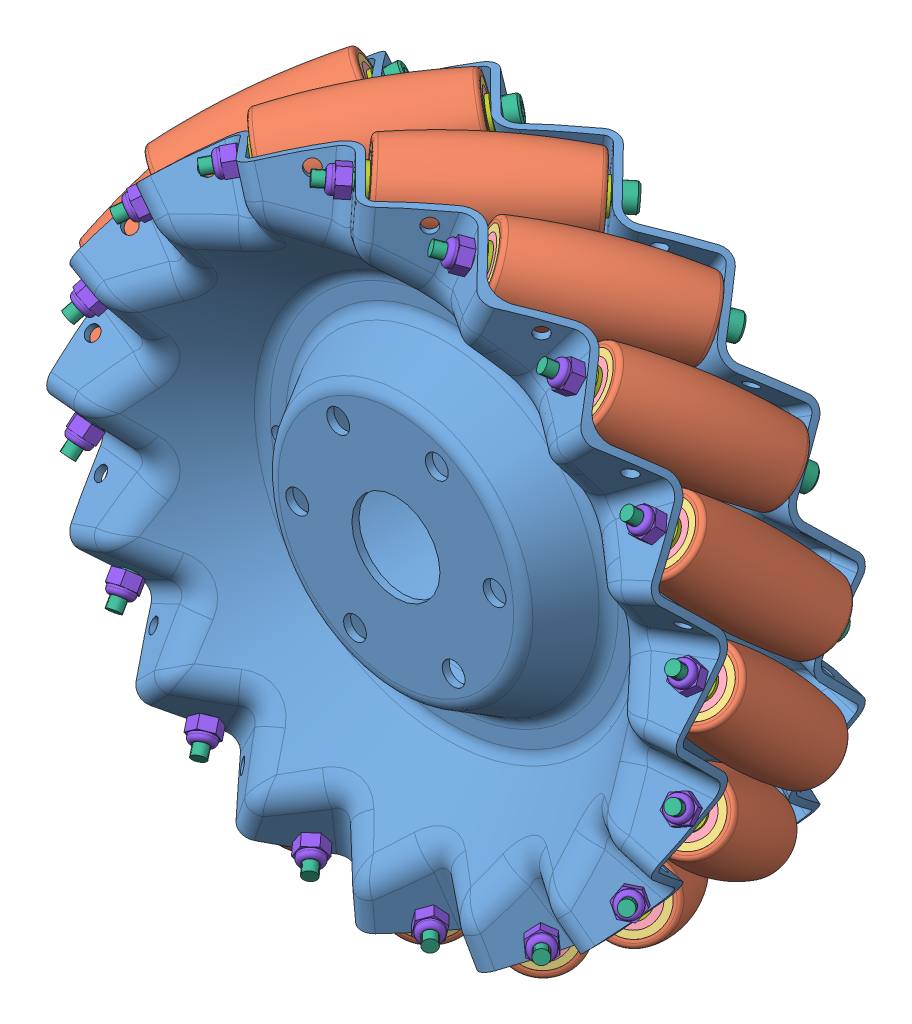
SolidWorks assembly 麦轮组装左, configuration 默认. Lengths in mm.
Overall size (168 168 53.18).
162 component instances, 8 part files, 5 mates.
Components (placement in the parent):
- 麦轮钣金-1: 麦轮钣金 [默认] at (-20.9276 7.6858 132.4522) size (142.88 142.88 24.05)
- 麦轮钣金-2: 麦轮钣金 [默认] at (-20.9276 7.6858 129.2518) x (-0.980785 -0.19509 0) z (0 0 -1) size (142.88 142.88 24.05)
- 滚花橡胶轮组装-1: 滚花橡胶轮组装 [默认] at (60.4121 -1.9858 154.8754) x (0.932849 -0.320965 -0.163627) z (-0.338043 -0.622763 -0.705615) size (18.5 18.5 53)
  - 滚花橡胶轮外-1: 滚花橡胶轮外 [默认] at (-9.896 1.7835 38.5971) size (18.5 18.5 38)
  - 滚花铝柱-1: 滚花铝柱 [默认] at (-9.896 1.7835 38) x (0.787441 0.61639 0) z (-0.61639 0.787441 0) size (13 38 13)
  - 轴承5X10X4-1: 轴承5X10X4 [默认] at (-9.896 1.7835 55) x (0.442498 0.896769 0) z (-0.896769 0.442498 0) size (10 4 10)
  - 轴承5X10X4-2: 轴承5X10X4 [默认] at (-9.896 1.7835 21) x (0.442498 0.896769 0) z (-0.896769 0.442498 0) size (10 4 10)
  - 铜管3X5-1: 铜管3X5 [默认] at (-9.896 1.7835 38) x (0.823254 0.567673 0) z (-0.567673 0.823254 0) size (5 38 5)
  - 螺丝-1: 螺丝 [默认] at (-9.896 1.7835 59.6) x (-0.462621 0.886556 0) z (0 0 1) size (5.5 5.5 53)
  - 垫片-1: 垫片 [默认] at (-9.896 1.7835 57) x (1 0 0) z (0 -1 0) size (7 0.8 7)
  - 垫片-2: 垫片 [默认] at (-9.896 1.7835 19) x (0.746862 -0.664979 0) z (0.664979 0.746862 0) size (7 0.8 7)
  - 螺母-1: 螺母 [默认] at (-9.896 1.7835 16.2) x (-0.766894 0.641774 0) z (0 0 -1) size (6.35 5.5 4.25)
- 滚花橡胶轮组装-2: 滚花橡胶轮组装 [默认] at (57.9216 29.8777 154.8754) x (0.984668 0.060453 -0.163627) z (-0.073989 -0.704722 -0.705615) size (18.5 18.5 53)
  - 滚花橡胶轮外-1: 滚花橡胶轮外 [默认] at (-9.896 1.7835 38.5971) size (18.5 18.5 38)
  - 滚花铝柱-1: 滚花铝柱 [默认] at (-9.896 1.7835 38) x (0.787441 0.61639 0) z (-0.61639 0.787441 0) size (13 38 13)
  - 轴承5X10X4-1: 轴承5X10X4 [默认] at (-9.896 1.7835 55) x (0.442498 0.896769 0) z (-0.896769 0.442498 0) size (10 4 10)
  - 轴承5X10X4-2: 轴承5X10X4 [默认] at (-9.896 1.7835 21) x (0.442498 0.896769 0) z (-0.896769 0.442498 0) size (10 4 10)
  - 铜管3X5-1: 铜管3X5 [默认] at (-9.896 1.7835 38) x (0.823254 0.567673 0) z (-0.567673 0.823254 0) size (5 38 5)
  - 螺丝-1: 螺丝 [默认] at (-9.896 1.7835 59.6) x (-0.462621 0.886556 0) z (0 0 1) size (5.5 5.5 53)
  - 垫片-1: 垫片 [默认] at (-9.896 1.7835 57) x (1 0 0) z (0 -1 0) size (7 0.8 7)
  - 垫片-2: 垫片 [默认] at (-9.896 1.7835 19) x (0.746862 -0.664979 0) z (0.664979 0.746862 0) size (7 0.8 7)
  - 螺母-1: 螺母 [默认] at (-9.896 1.7835 16.2) x (-0.766894 0.641774 0) z (0 0 -1) size (6.35 5.5 4.25)
- 滚花橡胶轮组装-3: 滚花橡胶轮组装 [默认] at (43.4271 58.3628 154.8754) x (0.88658 0.432668 -0.163627) z (0.201328 -0.679392 -0.705615) size (18.5 18.5 53)
  - 滚花橡胶轮外-1: 滚花橡胶轮外 [默认] at (-9.896 1.7835 38.5971) size (18.5 18.5 38)
  - 滚花铝柱-1: 滚花铝柱 [默认] at (-9.896 1.7835 38) x (0.787441 0.61639 0) z (-0.61639 0.787441 0) size (13 38 13)
  - 轴承5X10X4-1: 轴承5X10X4 [默认] at (-9.896 1.7835 55) x (0.442498 0.896769 0) z (-0.896769 0.442498 0) size (10 4 10)
  - 轴承5X10X4-2: 轴承5X10X4 [默认] at (-9.896 1.7835 21) x (0.442498 0.896769 0) z (-0.896769 0.442498 0) size (10 4 10)
  - 铜管3X5-1: 铜管3X5 [默认] at (-9.896 1.7835 38) x (0.823254 0.567673 0) z (-0.567673 0.823254 0) size (5 38 5)
  - 螺丝-1: 螺丝 [默认] at (-9.896 1.7835 59.6) x (-0.462621 0.886556 0) z (0 0 1) size (5.5 5.5 53)
  - 垫片-1: 垫片 [默认] at (-9.896 1.7835 57) x (1 0 0) z (0 -1 0) size (7 0.8 7)
  - 垫片-2: 垫片 [默认] at (-9.896 1.7835 19) x (0.746862 -0.664979 0) z (0.664979 0.746862 0) size (7 0.8 7)
  - 螺母-1: 螺母 [默认] at (-9.896 1.7835 16.2) x (-0.766894 0.641774 0) z (0 0 -1) size (6.35 5.5 4.25)
- 滚花橡胶轮组装-4: 滚花橡胶轮组装 [默认] at (19.1352 79.1327 154.8754) x (0.653519 0.739013 -0.163627) z (0.445995 -0.550632 -0.705615) size (18.5 18.5 53)
  - 滚花橡胶轮外-1: 滚花橡胶轮外 [默认] at (-9.896 1.7835 38.5971) size (18.5 18.5 38)
  - 滚花铝柱-1: 滚花铝柱 [默认] at (-9.896 1.7835 38) x (0.787441 0.61639 0) z (-0.61639 0.787441 0) size (13 38 13)
  - 轴承5X10X4-1: 轴承5X10X4 [默认] at (-9.896 1.7835 55) x (0.442498 0.896769 0) z (-0.896769 0.442498 0) size (10 4 10)
  - 轴承5X10X4-2: 轴承5X10X4 [默认] at (-9.896 1.7835 21) x (0.442498 0.896769 0) z (-0.896769 0.442498 0) size (10 4 10)
  - 铜管3X5-1: 铜管3X5 [默认] at (-9.896 1.7835 38) x (0.823254 0.567673 0) z (-0.567673 0.823254 0) size (5 38 5)
  - 螺丝-1: 螺丝 [默认] at (-9.896 1.7835 59.6) x (-0.462621 0.886556 0) z (0 0 1) size (5.5 5.5 53)
  - 垫片-1: 垫片 [默认] at (-9.896 1.7835 57) x (1 0 0) z (0 -1 0) size (7 0.8 7)
  - 垫片-2: 垫片 [默认] at (-9.896 1.7835 19) x (0.746862 -0.664979 0) z (0.664979 0.746862 0) size (7 0.8 7)
  - 螺母-1: 螺母 [默认] at (-9.896 1.7835 16.2) x (-0.766894 0.641774 0) z (0 0 -1) size (6.35 5.5 4.25)
- 滚花橡胶轮组装-5: 滚花橡胶轮组装 [默认] at (-11.256 89.0255 154.8754) x (0.320965 0.932849 -0.163627) z (0.622763 -0.338043 -0.705615) size (18.5 18.5 53)
  - 滚花橡胶轮外-1: 滚花橡胶轮外 [默认] at (-9.896 1.7835 38.5971) size (18.5 18.5 38)
  - 滚花铝柱-1: 滚花铝柱 [默认] at (-9.896 1.7835 38) x (0.787441 0.61639 0) z (-0.61639 0.787441 0) size (13 38 13)
  - 轴承5X10X4-1: 轴承5X10X4 [默认] at (-9.896 1.7835 55) x (0.442498 0.896769 0) z (-0.896769 0.442498 0) size (10 4 10)
  - 轴承5X10X4-2: 轴承5X10X4 [默认] at (-9.896 1.7835 21) x (0.442498 0.896769 0) z (-0.896769 0.442498 0) size (10 4 10)
  - 铜管3X5-1: 铜管3X5 [默认] at (-9.896 1.7835 38) x (0.823254 0.567673 0) z (-0.567673 0.823254 0) size (5 38 5)
  - 螺丝-1: 螺丝 [默认] at (-9.896 1.7835 59.6) x (-0.462621 0.886556 0) z (0 0 1) size (5.5 5.5 53)
  - 垫片-1: 垫片 [默认] at (-9.896 1.7835 57) x (1 0 0) z (0 -1 0) size (7 0.8 7)
  - 垫片-2: 垫片 [默认] at (-9.896 1.7835 19) x (0.746862 -0.664979 0) z (0.664979 0.746862 0) size (7 0.8 7)
  - 螺母-1: 螺母 [默认] at (-9.896 1.7835 16.2) x (-0.766894 0.641774 0) z (0 0 -1) size (6.35 5.5 4.25)
- 滚花橡胶轮组装-6: 滚花橡胶轮组装 [默认] at (-43.1195 86.535 154.8754) x (-0.060453 0.984668 -0.163627) z (0.704722 -0.073989 -0.705615) size (18.5 18.5 53)
  - 滚花橡胶轮外-1: 滚花橡胶轮外 [默认] at (-9.896 1.7835 38.5971) size (18.5 18.5 38)
  - 滚花铝柱-1: 滚花铝柱 [默认] at (-9.896 1.7835 38) x (0.787441 0.61639 0) z (-0.61639 0.787441 0) size (13 38 13)
  - 轴承5X10X4-1: 轴承5X10X4 [默认] at (-9.896 1.7835 55) x (0.442498 0.896769 0) z (-0.896769 0.442498 0) size (10 4 10)
  - 轴承5X10X4-2: 轴承5X10X4 [默认] at (-9.896 1.7835 21) x (0.442498 0.896769 0) z (-0.896769 0.442498 0) size (10 4 10)
  - 铜管3X5-1: 铜管3X5 [默认] at (-9.896 1.7835 38) x (0.823254 0.567673 0) z (-0.567673 0.823254 0) size (5 38 5)
  - 螺丝-1: 螺丝 [默认] at (-9.896 1.7835 59.6) x (-0.462621 0.886556 0) z (0 0 1) size (5.5 5.5 53)
  - 垫片-1: 垫片 [默认] at (-9.896 1.7835 57) x (1 0 0) z (0 -1 0) size (7 0.8 7)
  - 垫片-2: 垫片 [默认] at (-9.896 1.7835 19) x (0.746862 -0.664979 0) z (0.664979 0.746862 0) size (7 0.8 7)
  - 螺母-1: 螺母 [默认] at (-9.896 1.7835 16.2) x (-0.766894 0.641774 0) z (0 0 -1) size (6.35 5.5 4.25)
- 滚花橡胶轮组装-7: 滚花橡胶轮组装 [默认] at (-71.6045 72.0405 154.8754) x (-0.432668 0.88658 -0.163627) z (0.679392 0.201328 -0.705615) size (18.5 18.5 53)
  - 滚花橡胶轮外-1: 滚花橡胶轮外 [默认] at (-9.896 1.7835 38.5971) size (18.5 18.5 38)
  - 滚花铝柱-1: 滚花铝柱 [默认] at (-9.896 1.7835 38) x (0.787441 0.61639 0) z (-0.61639 0.787441 0) size (13 38 13)
  - 轴承5X10X4-1: 轴承5X10X4 [默认] at (-9.896 1.7835 55) x (0.442498 0.896769 0) z (-0.896769 0.442498 0) size (10 4 10)
  - 轴承5X10X4-2: 轴承5X10X4 [默认] at (-9.896 1.7835 21) x (0.442498 0.896769 0) z (-0.896769 0.442498 0) size (10 4 10)
  - 铜管3X5-1: 铜管3X5 [默认] at (-9.896 1.7835 38) x (0.823254 0.567673 0) z (-0.567673 0.823254 0) size (5 38 5)
  - 螺丝-1: 螺丝 [默认] at (-9.896 1.7835 59.6) x (-0.462621 0.886556 0) z (0 0 1) size (5.5 5.5 53)
  - 垫片-1: 垫片 [默认] at (-9.896 1.7835 57) x (1 0 0) z (0 -1 0) size (7 0.8 7)
  - 垫片-2: 垫片 [默认] at (-9.896 1.7835 19) x (0.746862 -0.664979 0) z (0.664979 0.746862 0) size (7 0.8 7)
  - 螺母-1: 螺母 [默认] at (-9.896 1.7835 16.2) x (-0.766894 0.641774 0) z (0 0 -1) size (6.35 5.5 4.25)
- 滚花橡胶轮组装-8: 滚花橡胶轮组装 [默认] at (-92.3745 47.7486 154.8754) x (-0.739013 0.653519 -0.163627) z (0.550632 0.445995 -0.705615) size (18.5 18.5 53)
  - 滚花橡胶轮外-1: 滚花橡胶轮外 [默认] at (-9.896 1.7835 38.5971) size (18.5 18.5 38)
  - 滚花铝柱-1: 滚花铝柱 [默认] at (-9.896 1.7835 38) x (0.787441 0.61639 0) z (-0.61639 0.787441 0) size (13 38 13)
  - 轴承5X10X4-1: 轴承5X10X4 [默认] at (-9.896 1.7835 55) x (0.442498 0.896769 0) z (-0.896769 0.442498 0) size (10 4 10)
  - 轴承5X10X4-2: 轴承5X10X4 [默认] at (-9.896 1.7835 21) x (0.442498 0.896769 0) z (-0.896769 0.442498 0) size (10 4 10)
  - 铜管3X5-1: 铜管3X5 [默认] at (-9.896 1.7835 38) x (0.823254 0.567673 0) z (-0.567673 0.823254 0) size (5 38 5)
  - 螺丝-1: 螺丝 [默认] at (-9.896 1.7835 59.6) x (-0.462621 0.886556 0) z (0 0 1) size (5.5 5.5 53)
  - 垫片-1: 垫片 [默认] at (-9.896 1.7835 57) x (1 0 0) z (0 -1 0) size (7 0.8 7)
  - 垫片-2: 垫片 [默认] at (-9.896 1.7835 19) x (0.746862 -0.664979 0) z (0.664979 0.746862 0) size (7 0.8 7)
  - 螺母-1: 螺母 [默认] at (-9.896 1.7835 16.2) x (-0.766894 0.641774 0) z (0 0 -1) size (6.35 5.5 4.25)
- 滚花橡胶轮组装-9: 滚花橡胶轮组装 [默认] at (-102.2673 17.3574 154.8754) x (-0.932849 0.320965 -0.163627) z (0.338043 0.622763 -0.705615) size (18.5 18.5 53)
  - 滚花橡胶轮外-1: 滚花橡胶轮外 [默认] at (-9.896 1.7835 38.5971) size (18.5 18.5 38)
  - 滚花铝柱-1: 滚花铝柱 [默认] at (-9.896 1.7835 38) x (0.787441 0.61639 0) z (-0.61639 0.787441 0) size (13 38 13)
  - 轴承5X10X4-1: 轴承5X10X4 [默认] at (-9.896 1.7835 55) x (0.442498 0.896769 0) z (-0.896769 0.442498 0) size (10 4 10)
  - 轴承5X10X4-2: 轴承5X10X4 [默认] at (-9.896 1.7835 21) x (0.442498 0.896769 0) z (-0.896769 0.442498 0) size (10 4 10)
  - 铜管3X5-1: 铜管3X5 [默认] at (-9.896 1.7835 38) x (0.823254 0.567673 0) z (-0.567673 0.823254 0) size (5 38 5)
  - 螺丝-1: 螺丝 [默认] at (-9.896 1.7835 59.6) x (-0.462621 0.886556 0) z (0 0 1) size (5.5 5.5 53)
  - 垫片-1: 垫片 [默认] at (-9.896 1.7835 57) x (1 0 0) z (0 -1 0) size (7 0.8 7)
  - 垫片-2: 垫片 [默认] at (-9.896 1.7835 19) x (0.746862 -0.664979 0) z (0.664979 0.746862 0) size (7 0.8 7)
  - 螺母-1: 螺母 [默认] at (-9.896 1.7835 16.2) x (-0.766894 0.641774 0) z (0 0 -1) size (6.35 5.5 4.25)
- 滚花橡胶轮组装-10: 滚花橡胶轮组装 [默认] at (-99.7768 -14.5061 154.8754) x (-0.984668 -0.060453 -0.163627) z (0.073989 0.704722 -0.705615) size (18.5 18.5 53)
  - 滚花橡胶轮外-1: 滚花橡胶轮外 [默认] at (-9.896 1.7835 38.5971) size (18.5 18.5 38)
  - 滚花铝柱-1: 滚花铝柱 [默认] at (-9.896 1.7835 38) x (0.787441 0.61639 0) z (-0.61639 0.787441 0) size (13 38 13)
  - 轴承5X10X4-1: 轴承5X10X4 [默认] at (-9.896 1.7835 55) x (0.442498 0.896769 0) z (-0.896769 0.442498 0) size (10 4 10)
  - 轴承5X10X4-2: 轴承5X10X4 [默认] at (-9.896 1.7835 21) x (0.442498 0.896769 0) z (-0.896769 0.442498 0) size (10 4 10)
  - 铜管3X5-1: 铜管3X5 [默认] at (-9.896 1.7835 38) x (0.823254 0.567673 0) z (-0.567673 0.823254 0) size (5 38 5)
  - 螺丝-1: 螺丝 [默认] at (-9.896 1.7835 59.6) x (-0.462621 0.886556 0) z (0 0 1) size (5.5 5.5 53)
  - 垫片-1: 垫片 [默认] at (-9.896 1.7835 57) x (1 0 0) z (0 -1 0) size (7 0.8 7)
  - 垫片-2: 垫片 [默认] at (-9.896 1.7835 19) x (0.746862 -0.664979 0) z (0.664979 0.746862 0) size (7 0.8 7)
  - 螺母-1: 螺母 [默认] at (-9.896 1.7835 16.2) x (-0.766894 0.641774 0) z (0 0 -1) size (6.35 5.5 4.25)
- 滚花橡胶轮组装-11: 滚花橡胶轮组装 [默认] at (-85.2823 -42.9912 154.8754) x (-0.88658 -0.432668 -0.163627) z (-0.201328 0.679392 -0.705615) size (18.5 18.5 53)
  - 滚花橡胶轮外-1: 滚花橡胶轮外 [默认] at (-9.896 1.7835 38.5971) size (18.5 18.5 38)
  - 滚花铝柱-1: 滚花铝柱 [默认] at (-9.896 1.7835 38) x (0.787441 0.61639 0) z (-0.61639 0.787441 0) size (13 38 13)
  - 轴承5X10X4-1: 轴承5X10X4 [默认] at (-9.896 1.7835 55) x (0.442498 0.896769 0) z (-0.896769 0.442498 0) size (10 4 10)
  - 轴承5X10X4-2: 轴承5X10X4 [默认] at (-9.896 1.7835 21) x (0.442498 0.896769 0) z (-0.896769 0.442498 0) size (10 4 10)
  - 铜管3X5-1: 铜管3X5 [默认] at (-9.896 1.7835 38) x (0.823254 0.567673 0) z (-0.567673 0.823254 0) size (5 38 5)
  - 螺丝-1: 螺丝 [默认] at (-9.896 1.7835 59.6) x (-0.462621 0.886556 0) z (0 0 1) size (5.5 5.5 53)
  - 垫片-1: 垫片 [默认] at (-9.896 1.7835 57) x (1 0 0) z (0 -1 0) size (7 0.8 7)
  - 垫片-2: 垫片 [默认] at (-9.896 1.7835 19) x (0.746862 -0.664979 0) z (0.664979 0.746862 0) size (7 0.8 7)
  - 螺母-1: 螺母 [默认] at (-9.896 1.7835 16.2) x (-0.766894 0.641774 0) z (0 0 -1) size (6.35 5.5 4.25)
- 滚花橡胶轮组装-12: 滚花橡胶轮组装 [默认] at (-60.9904 -63.7611 154.8754) x (-0.653519 -0.739013 -0.163627) z (-0.445995 0.550632 -0.705615) size (18.5 18.5 53)
  - 滚花橡胶轮外-1: 滚花橡胶轮外 [默认] at (-9.896 1.7835 38.5971) size (18.5 18.5 38)
  - 滚花铝柱-1: 滚花铝柱 [默认] at (-9.896 1.7835 38) x (0.787441 0.61639 0) z (-0.61639 0.787441 0) size (13 38 13)
  - 轴承5X10X4-1: 轴承5X10X4 [默认] at (-9.896 1.7835 55) x (0.442498 0.896769 0) z (-0.896769 0.442498 0) size (10 4 10)
  - 轴承5X10X4-2: 轴承5X10X4 [默认] at (-9.896 1.7835 21) x (0.442498 0.896769 0) z (-0.896769 0.442498 0) size (10 4 10)
  - 铜管3X5-1: 铜管3X5 [默认] at (-9.896 1.7835 38) x (0.823254 0.567673 0) z (-0.567673 0.823254 0) size (5 38 5)
  - 螺丝-1: 螺丝 [默认] at (-9.896 1.7835 59.6) x (-0.462621 0.886556 0) z (0 0 1) size (5.5 5.5 53)
  - 垫片-1: 垫片 [默认] at (-9.896 1.7835 57) x (1 0 0) z (0 -1 0) size (7 0.8 7)
  - 垫片-2: 垫片 [默认] at (-9.896 1.7835 19) x (0.746862 -0.664979 0) z (0.664979 0.746862 0) size (7 0.8 7)
  - 螺母-1: 螺母 [默认] at (-9.896 1.7835 16.2) x (-0.766894 0.641774 0) z (0 0 -1) size (6.35 5.5 4.25)
- 滚花橡胶轮组装-13: 滚花橡胶轮组装 [默认] at (-30.5992 -73.6539 154.8754) x (-0.320965 -0.932849 -0.163627) z (-0.622763 0.338043 -0.705615) size (18.5 18.5 53)
  - 滚花橡胶轮外-1: 滚花橡胶轮外 [默认] at (-9.896 1.7835 38.5971) size (18.5 18.5 38)
  - 滚花铝柱-1: 滚花铝柱 [默认] at (-9.896 1.7835 38) x (0.787441 0.61639 0) z (-0.61639 0.787441 0) size (13 38 13)
  - 轴承5X10X4-1: 轴承5X10X4 [默认] at (-9.896 1.7835 55) x (0.442498 0.896769 0) z (-0.896769 0.442498 0) size (10 4 10)
  - 轴承5X10X4-2: 轴承5X10X4 [默认] at (-9.896 1.7835 21) x (0.442498 0.896769 0) z (-0.896769 0.442498 0) size (10 4 10)
  - 铜管3X5-1: 铜管3X5 [默认] at (-9.896 1.7835 38) x (0.823254 0.567673 0) z (-0.567673 0.823254 0) size (5 38 5)
  - 螺丝-1: 螺丝 [默认] at (-9.896 1.7835 59.6) x (-0.462621 0.886556 0) z (0 0 1) size (5.5 5.5 53)
  - 垫片-1: 垫片 [默认] at (-9.896 1.7835 57) x (1 0 0) z (0 -1 0) size (7 0.8 7)
  - 垫片-2: 垫片 [默认] at (-9.896 1.7835 19) x (0.746862 -0.664979 0) z (0.664979 0.746862 0) size (7 0.8 7)
  - 螺母-1: 螺母 [默认] at (-9.896 1.7835 16.2) x (-0.766894 0.641774 0) z (0 0 -1) size (6.35 5.5 4.25)
- 滚花橡胶轮组装-14: 滚花橡胶轮组装 [默认] at (1.2643 -71.1634 154.8754) x (0.060453 -0.984668 -0.163627) z (-0.704722 0.073989 -0.705615) size (18.5 18.5 53)
  - 滚花橡胶轮外-1: 滚花橡胶轮外 [默认] at (-9.896 1.7835 38.5971) size (18.5 18.5 38)
  - 滚花铝柱-1: 滚花铝柱 [默认] at (-9.896 1.7835 38) x (0.787441 0.61639 0) z (-0.61639 0.787441 0) size (13 38 13)
  - 轴承5X10X4-1: 轴承5X10X4 [默认] at (-9.896 1.7835 55) x (0.442498 0.896769 0) z (-0.896769 0.442498 0) size (10 4 10)
  - 轴承5X10X4-2: 轴承5X10X4 [默认] at (-9.896 1.7835 21) x (0.442498 0.896769 0) z (-0.896769 0.442498 0) size (10 4 10)
  - 铜管3X5-1: 铜管3X5 [默认] at (-9.896 1.7835 38) x (0.823254 0.567673 0) z (-0.567673 0.823254 0) size (5 38 5)
  - 螺丝-1: 螺丝 [默认] at (-9.896 1.7835 59.6) x (-0.462621 0.886556 0) z (0 0 1) size (5.5 5.5 53)
  - 垫片-1: 垫片 [默认] at (-9.896 1.7835 57) x (1 0 0) z (0 -1 0) size (7 0.8 7)
  - 垫片-2: 垫片 [默认] at (-9.896 1.7835 19) x (0.746862 -0.664979 0) z (0.664979 0.746862 0) size (7 0.8 7)
  - 螺母-1: 螺母 [默认] at (-9.896 1.7835 16.2) x (-0.766894 0.641774 0) z (0 0 -1) size (6.35 5.5 4.25)
- 滚花橡胶轮组装-15: 滚花橡胶轮组装 [默认] at (29.7494 -56.6689 154.8754) x (0.432668 -0.88658 -0.163627) z (-0.679392 -0.201328 -0.705615) size (18.5 18.5 53)
  - 滚花橡胶轮外-1: 滚花橡胶轮外 [默认] at (-9.896 1.7835 38.5971) size (18.5 18.5 38)
  - 滚花铝柱-1: 滚花铝柱 [默认] at (-9.896 1.7835 38) x (0.787441 0.61639 0) z (-0.61639 0.787441 0) size (13 38 13)
  - 轴承5X10X4-1: 轴承5X10X4 [默认] at (-9.896 1.7835 55) x (0.442498 0.896769 0) z (-0.896769 0.442498 0) size (10 4 10)
  - 轴承5X10X4-2: 轴承5X10X4 [默认] at (-9.896 1.7835 21) x (0.442498 0.896769 0) z (-0.896769 0.442498 0) size (10 4 10)
  - 铜管3X5-1: 铜管3X5 [默认] at (-9.896 1.7835 38) x (0.823254 0.567673 0) z (-0.567673 0.823254 0) size (5 38 5)
  - 螺丝-1: 螺丝 [默认] at (-9.896 1.7835 59.6) x (-0.462621 0.886556 0) z (0 0 1) size (5.5 5.5 53)
  - 垫片-1: 垫片 [默认] at (-9.896 1.7835 57) x (1 0 0) z (0 -1 0) size (7 0.8 7)
  - 垫片-2: 垫片 [默认] at (-9.896 1.7835 19) x (0.746862 -0.664979 0) z (0.664979 0.746862 0) size (7 0.8 7)
  - 螺母-1: 螺母 [默认] at (-9.896 1.7835 16.2) x (-0.766894 0.641774 0) z (0 0 -1) size (6.35 5.5 4.25)
- 滚花橡胶轮组装-16: 滚花橡胶轮组装 [默认] at (50.5193 -32.377 154.8754) x (0.739013 -0.653519 -0.163627) z (-0.550632 -0.445995 -0.705615) size (18.5 18.5 53)
  - 滚花橡胶轮外-1: 滚花橡胶轮外 [默认] at (-9.896 1.7835 38.5971) size (18.5 18.5 38)
  - 滚花铝柱-1: 滚花铝柱 [默认] at (-9.896 1.7835 38) x (0.787441 0.61639 0) z (-0.61639 0.787441 0) size (13 38 13)
  - 轴承5X10X4-1: 轴承5X10X4 [默认] at (-9.896 1.7835 55) x (0.442498 0.896769 0) z (-0.896769 0.442498 0) size (10 4 10)
  - 轴承5X10X4-2: 轴承5X10X4 [默认] at (-9.896 1.7835 21) x (0.442498 0.896769 0) z (-0.896769 0.442498 0) size (10 4 10)
  - 铜管3X5-1: 铜管3X5 [默认] at (-9.896 1.7835 38) x (0.823254 0.567673 0) z (-0.567673 0.823254 0) size (5 38 5)
  - 螺丝-1: 螺丝 [默认] at (-9.896 1.7835 59.6) x (-0.462621 0.886556 0) z (0 0 1) size (5.5 5.5 53)
  - 垫片-1: 垫片 [默认] at (-9.896 1.7835 57) x (1 0 0) z (0 -1 0) size (7 0.8 7)
  - 垫片-2: 垫片 [默认] at (-9.896 1.7835 19) x (0.746862 -0.664979 0) z (0.664979 0.746862 0) size (7 0.8 7)
  - 螺母-1: 螺母 [默认] at (-9.896 1.7835 16.2) x (-0.766894 0.641774 0) z (0 0 -1) size (6.35 5.5 4.25)
Mates (geometry in assembly coordinates):
- 重合1: coincident: cylinder of 麦轮钣金-1 through (-20.9276 7.6858 156.2258) axis (0 0 -1) radius 10; circle of 麦轮钣金-2
- 同心1: concentric: cylinder of 麦轮钣金-1 through (18.3822 11.5575 132.4522) axis (0 0 1) radius 1.6; cylinder of 麦轮钣金-2 through (18.3822 11.5575 129.2518) axis (0 0 -1) radius 1.6
- 重合2: coincident: plane of 麦轮钣金-1 through (-6.402 80.7108 130.852) normal (0 0 -1); plane of 麦轮钣金-2 through (-49.4205 76.4738 130.852) normal (0 0 1)
- 同心2: concentric: cylinder of 麦轮钣金-2 through (31.352 -36.2023 116.7987) axis (0.338043 0.622763 0.705615) radius 1.6; cylinder of 滚花橡胶轮组装-1/螺丝-1 through (47.7132 -6.0607 150.9504) axis (-0.338043 -0.622763 -0.705615) radius 1.5
- 重合3: coincident: plane of 麦轮钣金-2 through (41.7027 -15.4076 91.2191) normal (-0.338043 -0.622763 -0.705615); plane of 滚花橡胶轮组装-1/螺丝-1 through (29.3206 -38.5302 117.5587) normal (0.338043 0.622763 0.705615)
